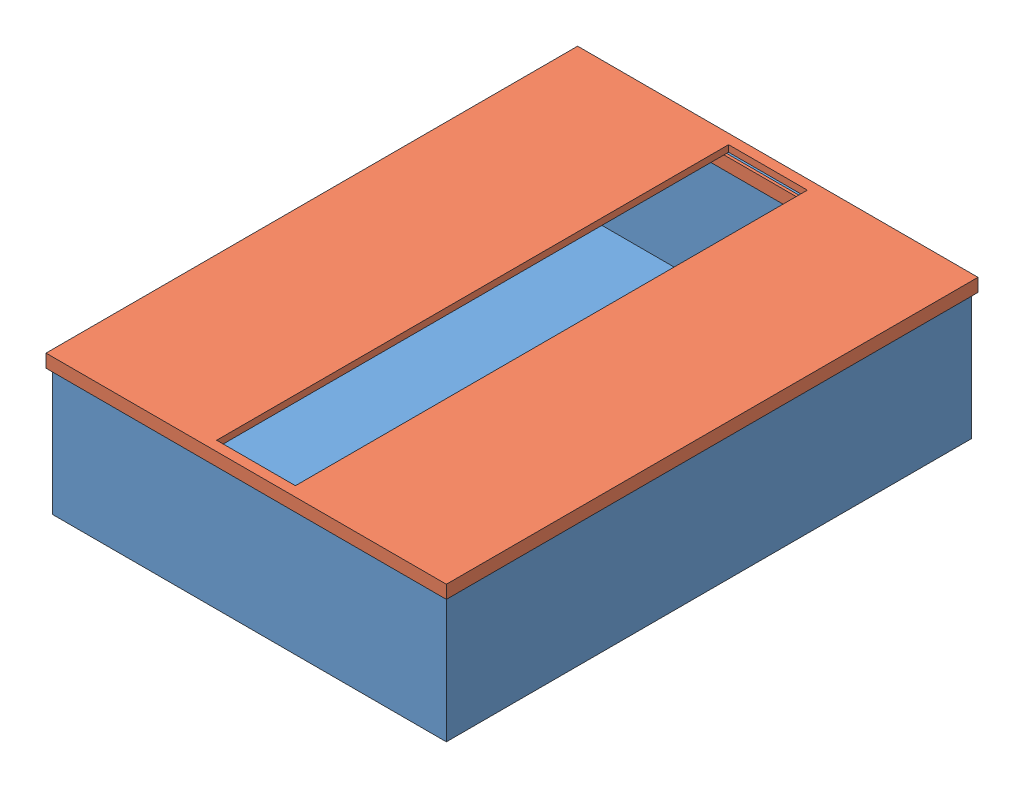
SolidWorks assembly Base, configuration Default. Lengths in mm.
Overall size (152.5 52.5 202.5).
2 component instances, 2 part files, 3 mates.
Components (placement in the parent):
- BS 1-1: BS 1 [Default] at (90.3644 102.493 247.3524) size (150 50 200)
- aaaa-1: aaaa [Default] at (89.6144 129.993 146.6024) size (152.5 7.5 202.5)
Mates (geometry in assembly coordinates):
- Coincident4: coincident anti-aligned: plane of BS 1-1 through (15.3644 127.493 47.3524) normal (0 1 0); plane of aaaa-1 through (89.6144 127.493 146.6024) normal (0 -1 0)
- Coincident5: coincident anti-aligned: plane of BS 1-1 through (162.8644 79.993 244.8524) normal (-1 0 0); plane of aaaa-1 through (162.8644 122.493 244.8524) normal (1 0 0)
- Coincident6: coincident anti-aligned: plane of BS 1-1 through (162.8644 79.993 244.8524) normal (0 0 -1); plane of aaaa-1 through (162.8644 122.493 244.8524) normal (0 0 1)
